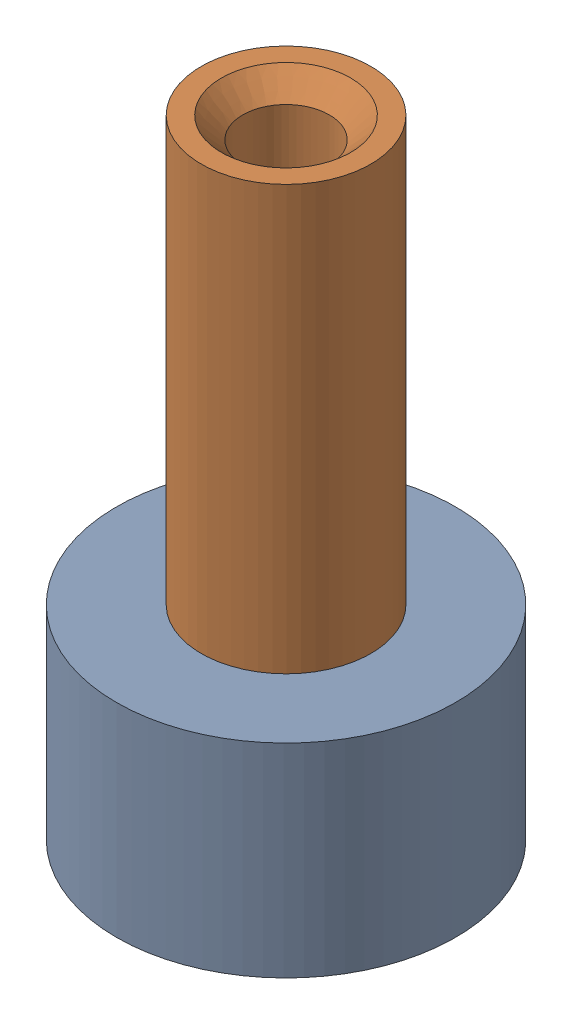
SolidWorks assembly Brake_rod_assy, configuration Default. Lengths in mm.
Overall size (20 37 20).
2 component instances, 2 part files, 2 mates.
Components (placement in the parent):
- Brake_rod_extender-1: Brake_rod_extender [Default] at (-3.2333 6.8564 1.1243) size (20 12 20)
- Brake_rod_locator-1: Brake_rod_locator [Default] at (-3.2333 31.8564 1.1243) x (0.953002 0 -0.302964) z (0.302964 0 0.953002) size (10 25 10)
Mates (geometry in assembly coordinates):
- Concentric1: concentric: circle of Brake_rod_extender-1; circle of Brake_rod_locator-1
- Coincident1: coincident anti-aligned: plane of Brake_rod_extender-1 through (-3.2333 6.8564 1.1243) normal (0 1 0); plane of Brake_rod_locator-1 through (-3.2333 6.8564 1.1243) normal (0 -1 0)
